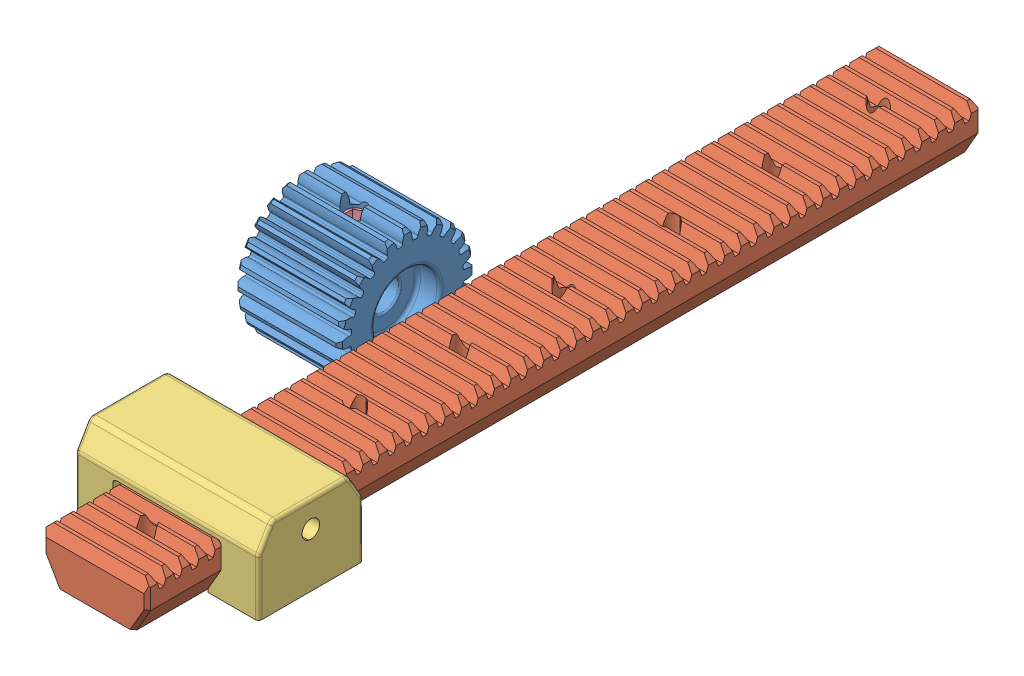
SolidWorks assembly Example Rack & Pinion, configuration Default. Lengths in mm.
Overall size (46 22.53 127.5).
4 component instances, 4 part files, 0 mates.
Components (placement in the parent):
- Tetrix Slide Pinion-1: Tetrix Slide Pinion [Default] at origin size (16.01 20.8 20.8)
- Tetrix Slide Rack-1: Tetrix Slide Rack [Default] at (24 0 0) size (16 7.65 127.5)
- Tetrix Slide Carriage-1: Tetrix Slide Carriage [Default] at (24 8.125 44.7523) x (-1 0 0) z (0 0 1) size (28 12.25 16)
- Tetrix Slide Pinion Set Screw-1: Tetrix Slide Pinion Set Screw [Default] at (0 1.975 0) x (0.5 0 0.866025) z (-0.866025 0 0.5) size (4.03 6.51 3.99)
